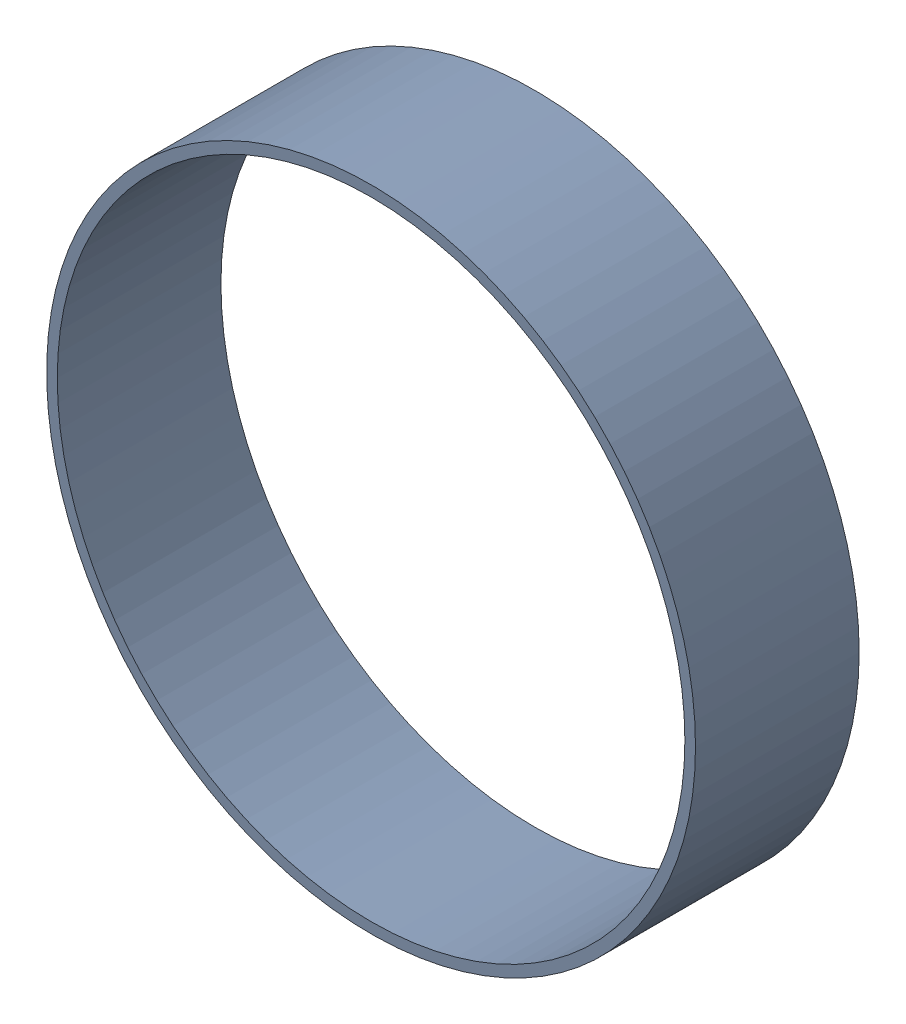
SolidWorks assembly Pad Free-4(36.068mm,62.992mm) on Multi-Layer, configuration Predeterminado. Lengths in mm.
Overall size (1.55 1.55 0.39).
2 component instances, 1 part files, 0 mates.
Components (placement in the parent):
- Pad Hole-2-1: Pad Hole-2 [Predeterminado] at (36.068 62.992 -0.4013) size (1.55 1.55 0.39)
  - Pad Hole-Part-1-2-1: Pad Hole-Part-1-2 [Predeterminado] at origin size (1.55 1.55 0.39)
